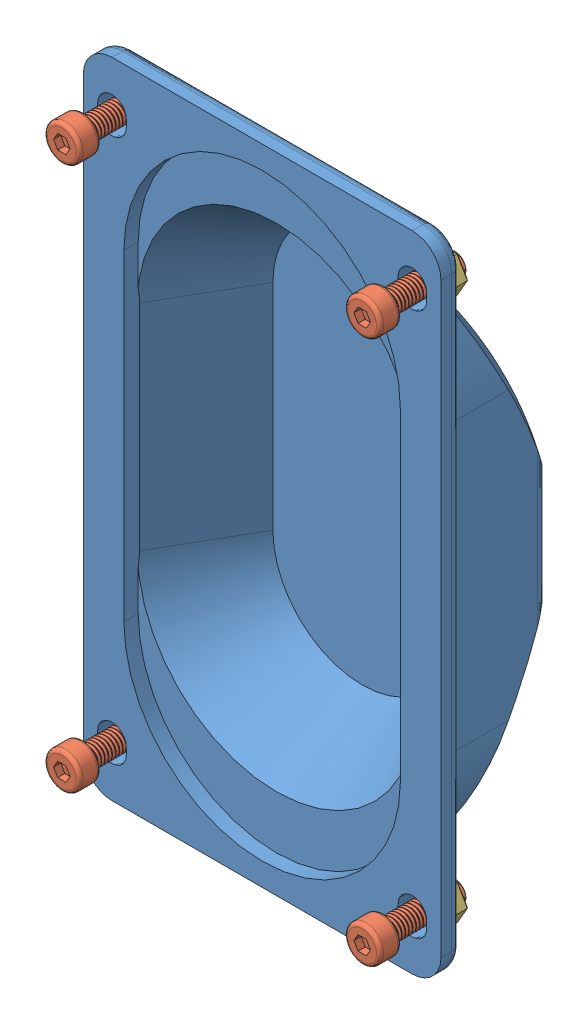
SolidWorks assembly Parl, configuration Predeterminado. Lengths in mm.
Overall size (50 90 30.01).
9 component instances, 3 part files, 16 mates.
Components (placement in the parent):
- Parlante-1: Parlante [Predeterminado] at (-17.2172 -4.3793 98.5) size (50 90 23)
- Tornillo M3x10_CC-1: Tornillo M3x10_CC [Predeterminado] at (-38.2172 33.6207 95.51) size (5 5 13)
- Tornillo M3x10_CC-2: Tornillo M3x10_CC [Predeterminado] at (3.7828 33.6207 95.51) size (5 5 13)
- Tornillo M3x10_CC-3: Tornillo M3x10_CC [Predeterminado] at (-38.2172 -42.3793 95.51) size (5 5 13)
- Tornillo M3x10_CC-4: Tornillo M3x10_CC [Predeterminado] at (3.7828 -42.3793 95.51) size (5 5 13)
- Tuerca M3-1: Tuerca M3 [Predeterminado] at (-38.2172 33.6207 96.5) x (1 0 0) z (0 -1 0) size (5.77 2 5)
- Tuerca M3-2: Tuerca M3 [Predeterminado] at (3.7828 33.6207 96.5) x (1 0 0) z (0 -1 0) size (5.77 2 5)
- Tuerca M3-3: Tuerca M3 [Predeterminado] at (3.7828 -42.3793 96.5) x (1 0 0) z (0 -1 0) size (5.77 2 5)
- Tuerca M3-4: Tuerca M3 [Predeterminado] at (-38.2172 -42.3793 96.5) x (1 0 0) z (0 -1 0) size (5.77 2 5)
Mates (geometry in assembly coordinates):
- Coincidente1: coincident aligned: plane of Tornillo M3x10_CC-1 through (-38.2172 33.6207 108.51) normal (0 0 1); plane of Tornillo M3x10_CC-2 through (3.7828 33.6207 108.51) normal (0 0 1)
- Coincidente2: coincident aligned: plane of Tornillo M3x10_CC-2 through (3.7828 33.6207 108.51) normal (0 0 1); plane of Tornillo M3x10_CC-3 through (-38.2172 -42.3793 108.51) normal (0 0 1)
- Coincidente3: coincident aligned: plane of Tornillo M3x10_CC-3 through (-38.2172 -42.3793 108.51) normal (0 0 1); plane of Tornillo M3x10_CC-4 through (3.7828 -42.3793 108.51) normal (0 0 1)
- Ranura1: slot aligned: cylinder of Tornillo M3x10_CC-1 through (-38.2172 33.6207 108.51) axis (0 0 -1) radius 2.5; plane of Parlante-1 through (-36.2172 34.1207 101.5) normal (-1 0 0); cylinder of Parlante-1 through (-38.2172 33.1207 101.5) axis (0 0 -1) radius 2
- Distancia1: distance = 4.01 mm anti-aligned: plane of Tornillo M3x10_CC-1 through (-38.2172 33.6207 105.51) normal (0 0 -1); plane of Parlante-1 through (-38.2172 -45.3793 101.5) normal (0 0 1)
- Ranura2: slot aligned: cylinder of Tornillo M3x10_CC-2 through (3.7828 33.6207 108.51) axis (0 0 -1) radius 2.5; plane of Parlante-1 through (5.7828 34.1207 101.5) normal (-1 0 0); cylinder of Parlante-1 through (3.7828 33.1207 101.5) axis (0 0 -1) radius 2
- Ranura3: slot aligned: cylinder of Tornillo M3x10_CC-3 through (-38.2172 -42.3793 108.51) axis (0 0 -1) radius 2.5; plane of Parlante-1 through (-36.2172 -42.8793 101.5) normal (-1 0 0); cylinder of Parlante-1 through (-38.2172 -42.8793 101.5) axis (0 0 -1) radius 2
- Ranura4: slot aligned: cylinder of Tornillo M3x10_CC-4 through (3.7828 -42.3793 108.51) axis (0 0 -1) radius 2.5; plane of Parlante-1 through (5.7828 -42.8793 101.5) normal (-1 0 0); cylinder of Parlante-1 through (3.7828 -42.8793 101.5) axis (0 0 -1) radius 2
- Coincidente6: coincident aligned: plane of Tuerca M3-1 through (-38.2172 33.6207 98.5) normal (0 0 1); plane of Tuerca M3-3 through (2.2393 -38.2929 97.6098) normal (0 0 1)
- Coincidente7: coincident aligned: plane of Tuerca M3-3 through (2.2393 -38.2929 97.6098) normal (0 0 1); plane of Tuerca M3-4 through (-38.2172 -42.3793 98.5) normal (0 0 1)
- Coincidente8: coincident aligned: plane of Tuerca M3-1 through (-38.2172 33.6207 98.5) normal (0 0 1); plane of Tuerca M3-2 through (3.7828 33.6207 98.5) normal (0 0 1)
- Concéntrica1: concentric aligned: circle of Tornillo M3x10_CC-1; circle of Tuerca M3-1
- Coincidente9: coincident anti-aligned: plane of Parlante-1 through (-38.2172 -45.3793 98.5) normal (0 0 -1); plane of Tuerca M3-1 through (-38.2172 33.6207 98.5) normal (0 0 1)
- Concéntrica2: concentric aligned: circle of Tornillo M3x10_CC-2; circle of Tuerca M3-2
- Concéntrica3: concentric anti-aligned: circle of Tornillo M3x10_CC-3; circle of Tuerca M3-4
- Concéntrica4: concentric aligned: circle of Tornillo M3x10_CC-4; circle of Tuerca M3-3
